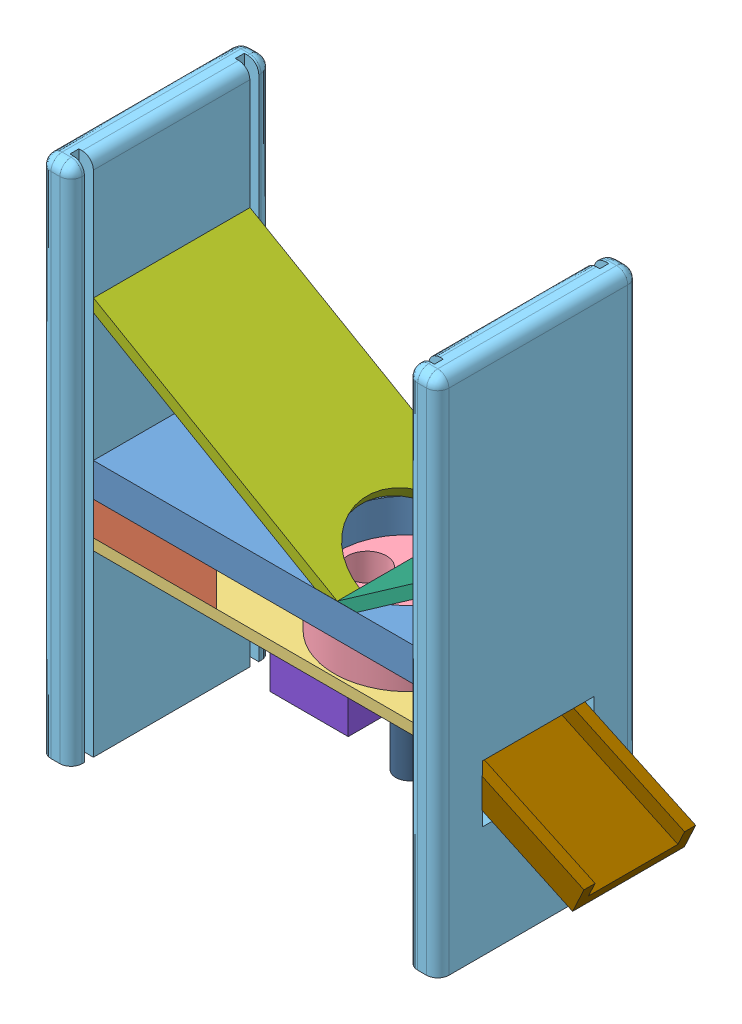
SolidWorks assembly MAIN, configuration Default. Lengths in mm.
Overall size (284.1 295.28 117.28).
13 component instances, 11 part files, 33 mates.
Components (placement in the parent):
- CenterDrop-1: CenterDrop [Default] at (73.1589 98.988 145.4321) size (190.5 19.05 88.9)
- Spacer-1: Spacer [Default] at (12.8339 79.938 145.4321) x (1 0 0) z (0 -1 0) size (69.85 88.9 19.05)
- ShaftPlate-1: ShaftPlate [Default] at (73.1589 67.238 145.4321) x (-1 0 0) z (0 -1 0) size (190.5 88.9 6.35)
- Indexer-1: Indexer [Default] at (113.1639 79.938 145.4321) x (0.863177 0 -0.504901) z (0 -1 0) size (85.72 85.72 19.05)
- SidePanel-1: SidePanel [Right] at (-30.9811 110.1005 145.4321) x (0 0 -1) z (1 0 0) size (114.3 295.28 17.78)
- SidePanel-2: SidePanel [Left] at (177.2989 110.1005 145.3686) x (0 0 1) z (-1 0 0) size (114.3 295.28 17.78)
- SlidePanel-1: SlidePanel [Default] at (73.1589 111.688 192.3586) size (207.01 292.1 5.08) (hidden)
- SmallAngle-1: SmallAngle [Default] at (144.222 124.1232 145.3686) x (0 0 -1) z (0.819152 0.573576 0) size (88.9 10.92 68.6)
- BigAngle-2: BigAngle [Default] at (53.2465 141.3043 145.3686) x (0 0 1) z (-0.866025 0.5 0) size (88.9 6.35 159.91)
- SlidePanel-2: SlidePanel [Default] at (73.1589 111.688 98.3786) size (207.01 292.1 5.08) (hidden)
- MotorBlock-1: MotorBlock [Default] at (100.4639 54.538 189.8821) size (44.45 19.05 88.9)
- Ramp-3: Ramp [Default] at (181.5813 40.1042 113.9946) x (-0.906308 0.422618 0) z (0 0 -1) size (127 15.24 63.5)
- Shaft_extender-1: Shaft_extender [Default] at (113.1639 1.833 145.4321) size (15.88 76.2 15.88)
Mates (geometry in assembly coordinates):
- Coincident1: coincident anti-aligned: plane of CenterDrop-1 through (73.1589 89.463 145.4321) normal (0 -1 0); plane of Spacer-1 through (12.8339 89.463 145.4321) normal (0 1 0)
- Coincident2: coincident aligned: plane of CenterDrop-1 through (-22.0911 108.513 100.9821) normal (-1 0 0); plane of Spacer-1 through (-22.0911 70.413 145.4321) normal (-1 0 0)
- Coincident3: coincident aligned: plane of CenterDrop-1 through (-22.0911 108.513 100.9821) normal (0 0 -1); plane of Spacer-1 through (12.8339 70.413 100.9821) normal (0 0 -1)
- Coincident5: coincident anti-aligned: plane of Spacer-1 through (12.8339 70.413 145.4321) normal (0 -1 0); plane of ShaftPlate-1 through (73.1589 70.413 145.4321) normal (0 1 0)
- Coincident6: coincident aligned: plane of CenterDrop-1 through (168.4089 108.513 100.9821) normal (1 0 0); plane of ShaftPlate-1 through (168.4089 64.063 100.9821) normal (1 0 0)
- Coincident7: coincident aligned: plane of Spacer-1 through (12.8339 70.413 100.9821) normal (0 0 -1); plane of ShaftPlate-1 through (168.4089 64.063 100.9821) normal (0 0 -1)
- Coincident8: coincident anti-aligned: plane of ShaftPlate-1 through (73.1589 70.413 145.4321) normal (0 1 0); plane of Indexer-1 through (113.1639 70.413 145.4321) normal (0 -1 0)
- Concentric1: concentric anti-aligned: cylinder of ShaftPlate-1 through (113.1639 64.063 145.4321) axis (0 1 0) radius 7.9375; cylinder of Indexer-1 through (113.1639 78.033 145.4321) axis (0 -1 0) radius 7.9375
- Coincident12: coincident anti-aligned: plane of CenterDrop-1 through (168.4089 108.513 100.9821) normal (1 0 0); plane of SidePanel-2 through (168.4089 110.1005 145.3686) normal (-1 0 0)
- Coincident13: coincident anti-aligned: plane of CenterDrop-1 through (-22.0911 108.513 100.9821) normal (-1 0 0); plane of SidePanel-1 through (-22.0911 110.1005 145.4321) normal (1 0 0)
- Concentric3: concentric anti-aligned: cylinder of CenterDrop-1 through (155.7089 98.988 162.8946) axis (1 0 0) radius 3.175; cylinder of SidePanel-2 through (181.1089 98.988 162.8946) axis (-1 0 0) radius 3.175
- Coincident14: coincident aligned: plane of CenterDrop-1 through (-22.0911 108.513 100.9821) normal (0 0 -1); plane of SidePanel-1 through (-22.0911 -37.537 100.9821) normal (0 0 -1)
- Parallel1: parallel aligned: plane of ShaftPlate-1 through (168.4089 64.063 100.9821) normal (0 0 -1); plane of SidePanel-2 through (168.4089 -37.537 100.9186) normal (0 0 -1)
- Coincident19: coincident anti-aligned: plane of SidePanel-2 through (168.4089 -37.537 194.8986) normal (0 0 -1); plane of SlidePanel-1 through (73.1589 111.688 194.8986) normal (0 0 1)
- Coincident20: coincident anti-aligned: plane of SidePanel-2 through (176.6639 -37.537 194.8986) normal (-1 0 0); plane of SlidePanel-1 through (176.6639 257.738 194.8986) normal (1 0 0)
- Coincident21: coincident aligned: plane of SidePanel-2 through (168.4089 257.738 88.2186) normal (0 1 0); plane of SlidePanel-1 through (-30.3461 257.738 194.8986) normal (0 1 0)
- Coincident23: coincident aligned: plane of SidePanel-1 through (-22.0911 -37.537 202.5821) normal (0 -1 0); plane of SidePanel-2 through (168.4089 -37.537 88.2186) normal (0 -1 0)
- Coincident28: coincident anti-aligned: plane of SidePanel-2 through (168.4089 110.1005 145.3686) normal (-1 0 0); plane of SmallAngle-1 through (168.4089 124.1232 100.9186) normal (1 0 0)
- Coincident29: coincident anti-aligned: plane of SlidePanel-1 through (73.1589 111.688 189.8186) normal (0 0 -1); plane of SmallAngle-1 through (144.222 124.1232 189.8186) normal (0 0 1)
- Coincident35: coincident anti-aligned: plane of SlidePanel-1 through (73.1589 111.688 189.8186) normal (0 0 -1); plane of BigAngle-2 through (53.2465 141.3043 189.8186) normal (0 0 1)
- Coincident38: coincident anti-aligned: line of SmallAngle-1 through (116.3928 108.513 100.9186) axis (0 0 1); line of BigAngle-2 through (116.3928 108.513 189.8186) axis (0 0 -1)
- Coincident39: coincident anti-aligned: plane of CenterDrop-1 through (73.1589 108.513 145.4321) normal (0 1 0); plane of BigAngle-2 through (53.2465 108.513 189.8186) normal (0 -1 0)
- Coincident45: coincident anti-aligned: plane of SidePanel-2 through (168.4089 -37.537 100.9186) normal (0 0 -1); plane of SlidePanel-2 through (73.1589 111.688 100.9186) normal (0 0 1)
- Coincident46: coincident anti-aligned: plane of SidePanel-1 through (-30.3461 -37.537 95.9021) normal (1 0 0); plane of SlidePanel-2 through (-30.3461 257.738 100.9186) normal (-1 0 0)
- Coincident47: coincident aligned: plane of SidePanel-2 through (168.4089 257.738 88.2186) normal (0 1 0); plane of SlidePanel-2 through (-30.3461 257.738 100.9186) normal (0 1 0)
- Coincident48: coincident anti-aligned: plane of ShaftPlate-1 through (73.1589 64.063 145.4321) normal (0 -1 0); plane of MotorBlock-1 through (78.2389 64.063 100.9821) normal (0 1 0)
- Coincident49: coincident aligned: plane of ShaftPlate-1 through (168.4089 64.063 189.8821) normal (0 0 1); plane of MotorBlock-1 through (100.4639 54.538 189.8821) normal (0 0 1)
- Distance1: distance = 45.72 mm anti-aligned: plane of SidePanel-2 through (168.4089 110.1005 145.3686) normal (-1 0 0); plane of MotorBlock-1 through (122.6889 64.063 100.9821) normal (1 0 0)
- Coincident72: coincident anti-aligned: plane of ShaftPlate-1 through (73.1589 64.063 145.4321) normal (0 -1 0); plane of Ramp-3 through (153.3116 64.063 101.5185) normal (0 1 0)
- Coincident74: coincident anti-aligned: plane of ShaftPlate-1 through (73.1589 64.063 145.4321) normal (0 -1 0); plane of Ramp-3 through (122.6889 64.063 177.4946) normal (0 1 0)
- Coincident75: coincident: plane of MotorBlock-1 through (122.6889 64.063 100.9821) normal (1 0 0); line of Ramp-3 through (122.6889 64.063 177.4946) axis (0 0 -1)
- Coincident76: coincident anti-aligned: plane of Indexer-1 through (113.1639 78.033 145.4321) normal (0 -1 0); circle of Shaft_extender-1
- Coincident77: coincident anti-aligned: circle of Indexer-1; circle of Shaft_extender-1
